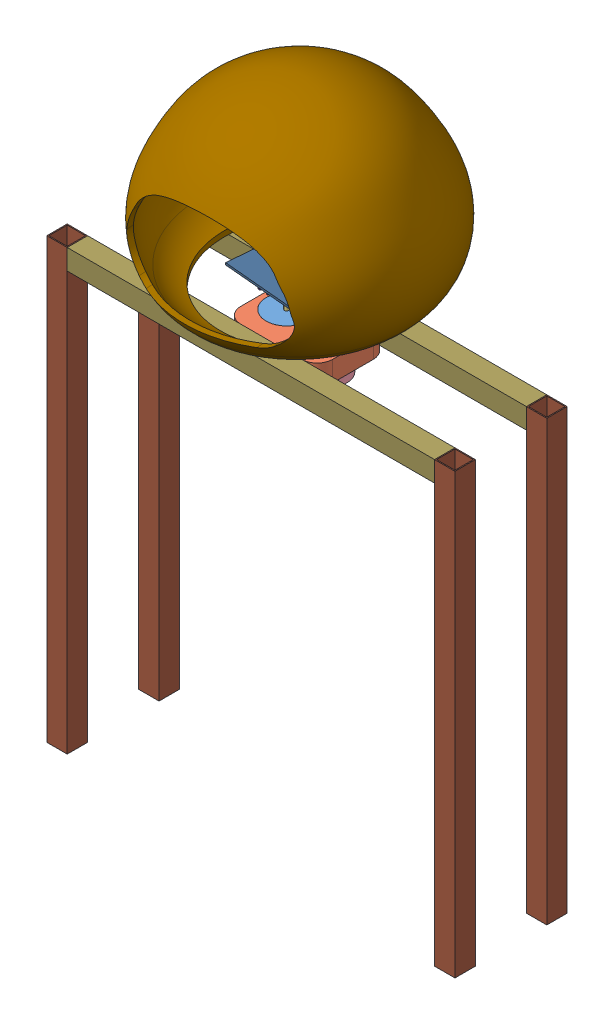
SolidWorks assembly Assemminubotmechanism1, configuration Default. Lengths in mm.
Overall size (400 641.82 258.29).
25 component instances, 13 part files, 41 mates.
Components (placement in the parent):
- motor-1: motor [Default] at (41.8736 82.6151 282.3269) x (-0.996078 0 -0.088478) z (0.08601 0.234536 -0.968295) size (40 40 40)
- motor-2: motor [Default] at (-7.9303 10.615 277.903) x (0 -1 0) z (0.040823 0 0.999166) size (40 40 40)
- support-2: support [Default] at (107.0697 -79.385 138.7286) x (-1 0 0) z (0 0 -1) size (50 90 70) (hidden)
- motorholder-2: motorholder [Default] at (12.0697 -9.385 277.903) x (1 0 0) z (0 1 0) size (90 70 20)
- motorshaft-1: motorshaft [Default] at (-7.9303 30.615 277.903) x (0.099455 0 -0.995042) z (0 -1 0) size (4 4 20)
- encoder-1: encoder [Default] at (32.0697 -22.385 277.903) x (0 1 0) z (-0.896169 0 0.443712) size (33 38 38)
- encoder-2: encoder [Default] at (9.003 122.6151 279.4071) x (0.996078 0 0.088478) z (0.000918 -0.999946 -0.01033) size (33 38 38)
- motorshaft-2: motorshaft [Default] at (61.7951 82.6151 284.0965) x (-0.033785 0.924225 0.380352) z (-0.996078 0 -0.088478) size (4 4 20)
- encodershaft-2: encodershaft [Default] at (41.8736 122.6151 282.3269) x (-0.064638 0.682856 0.727688) z (0.996078 0 0.088478) size (3 3 15)
- encodershaft-3: encodershaft [Default] at (32.0697 25.615 277.903) x (0.479617 0 -0.877478) z (0 -1 0) size (3 3 15)
- l link1-1: l link1 [Default] at (81.4955 53.9444 254.4504) x (-0.003837 0.999059 0.043201) z (-0.088395 -0.043371 0.995141) size (112 115 60)
- encodershaftcoupling-1: encodershaftcoupling [Default] at (32.0697 40.615 277.903) x (-0.852707 0 -0.522389) z (0 -1 0) size (10 10 15)
- encodershaftcoupling-2: encodershaftcoupling [Default] at (71.7559 122.6151 284.9813) x (0.065115 0.677039 -0.733061) z (-0.996078 0 -0.088478) size (10 10 15)
- spur gear_am-12: spur gear_am [Metric - Spur gear 2.5M 16T 20PA 10FW ---S16O15H20L10N] at (-7.9303 35.6151 277.903) x (0 1 0) z (-0.944824 0 0.327578) size (20 44.35 44.35)
- spur gear_am-13: spur gear_am [Metric - Spur gear 2.5M 16T 20PA 10FW ---S16O15H20L10N] at (32.0697 35.6151 277.903) x (0 1 0) z (0.661693 0 -0.749775) size (20 44.35 44.35)
- spur gear_am-14: spur gear_am [Metric - Spur gear 2.5M 16T 20PA 10FW ---S16O15H20L10N] at (66.7756 122.6151 284.5389) x (0.996078 0 0.088478) z (-0.048006 -0.840007 0.540447) size (20 44.35 44.35)
- spur gear_am-15: spur gear_am [Metric - Spur gear 2.5M 16T 20PA 10FW ---S16O15H20L10N] at (66.7756 82.6151 284.5389) x (0.996078 0 0.088478) z (-0.043333 -0.871856 0.487842) size (20 44.35 44.35)
- FaceEVE2-1: FaceEVE2 [Default] at (7.0992 59.6367 278.2366) x (0.035057 -0.04304 0.998458) z (-0.999378 -0.005346 0.034859) size (242.26 184.23 242.26)
- l link-2: l link [Default] at (14.489 70.3565 310.0125) x (-0.996078 0 -0.088478) z (0.088478 0 -0.996078) size (80 100 60)
- head channel430mm-1: head channel430mm [Default] at (-187.9303 -419.385 222.903) x (1 0 0) z (0 1 0) size (20 20 430)
- head channel430mm-2: head channel430mm [Default] at (-187.9303 10.615 332.903) x (1 0 0) z (0 -1 0) size (20 20 430)
- head channel-5: head channel [Default] at (192.0697 10.615 222.903) x (0 0 1) z (-1 0 0) size (20 20 360)
- head channel-6: head channel [Default] at (-167.9303 10.615 332.903) x (0 0 -1) z (1 0 0) size (20 20 360)
- head channel430mm-5: head channel430mm [Default] at (212.0697 -419.385 332.903) x (-1 0 0) z (0 1 0) size (20 20 430)
- head channel430mm-6: head channel430mm [Default] at (212.0697 10.615 222.903) x (-1 0 0) z (0 -1 0) size (20 20 430)
Mates (geometry in assembly coordinates):
- Coincident1: coincident anti-aligned: circle of motor-2; circle of motorshaft-1
- Coincident2: coincident anti-aligned: circle of motor-1; circle of motorshaft-2
- Coincident6: coincident aligned: circle of encoder-2; circle of encodershaft-2
- Coincident11: coincident anti-aligned: cylinder of motor-2 through (-7.9303 -29.385 277.903) axis (0 1 0) radius 20; circle of motorholder-2
- Coincident17: coincident anti-aligned: line of support-2 through (57.0697 10.615 68.7286) axis (0 0 1); line of motorholder-2 through (57.0697 10.615 297.903) axis (0 0 -1)
- Coincident18: coincident anti-aligned: plane of support-2 through (57.0697 -79.385 68.7286) normal (-1 0 0); plane of motorholder-2 through (57.0697 10.615 297.903) normal (1 0 0)
- Coincident28: coincident aligned: plane of motor-2 through (-7.9303 10.615 277.903) normal (0 1 0); plane of motorholder-2 through (-17.9303 10.615 297.903) normal (0 1 0)
- Concentric9: concentric aligned: circle of encodershaft-3; circle of encodershaftcoupling-1
- Concentric12: concentric anti-aligned: circle of encodershaft-2; circle of encodershaftcoupling-2
- Coincident76: coincident aligned: circle of motorholder-2; circle of encoder-1
- Coincident77: coincident anti-aligned: circle of encoder-1; circle of encodershaft-3
- Coincident92: coincident anti-aligned: circle of encodershaftcoupling-1; circle of spur gear_am-13
- GearMate2: gear = 15 : 15 mm: circle of spur gear_am-12; circle of spur gear_am-13
- Coincident95: coincident anti-aligned: circle of encodershaftcoupling-2; circle of spur gear_am-14
- GearMate3: gear = 15 : 15 mm: circle of spur gear_am-14; circle of spur gear_am-15
- Coincident97: coincident aligned: circle of motor-1; circle of l link-2
- Coincident98: coincident anti-aligned: circle of encoder-2; circle of l link-2
- Width1: width anti-aligned: plane of head channel-6 through (192.0697 10.615 332.903) normal (1 0 0); plane of head channel-6 through (-167.9303 10.615 332.903) normal (-1 0 0); plane of motorholder-2 through (-32.9303 10.615 297.903) normal (-1 0 0); plane of motorholder-2 through (57.0697 10.615 297.903) normal (1 0 0)
- Coincident102: coincident anti-aligned: line of motorholder-2 through (-17.9303 10.615 312.903) axis (1 0 0); line of head channel-6 through (192.0697 10.615 312.903) axis (-1 0 0)
- Coincident103: coincident anti-aligned: plane of motorholder-2 through (42.0697 10.615 312.903) normal (0 0 1); plane of head channel-6 through (192.0697 10.615 312.903) normal (0 0 -1)
- Coincident104: coincident anti-aligned: plane of motorholder-2 through (42.0697 10.615 242.903) normal (0 0 -1); plane of head channel-5 through (-167.9303 10.615 242.903) normal (0 0 1)
- Width2: width aligned: plane of head channel-5 through (-167.9303 10.615 222.903) normal (-1 0 0); plane of head channel-5 through (192.0697 10.615 222.903) normal (1 0 0); plane of motorholder-2 through (-32.9303 10.615 297.903) normal (-1 0 0); plane of motorholder-2 through (57.0697 10.615 297.903) normal (1 0 0)
- Coincident105: coincident anti-aligned: line of motorholder-2 through (42.0697 10.615 242.903) axis (-1 0 0); line of head channel-5 through (-167.9303 10.615 242.903) axis (1 0 0)
- Coincident106: coincident aligned: line of head channel430mm-2 through (-167.9303 10.615 312.903) axis (0 0 1); line of head channel-6 through (-167.9303 10.615 312.903) axis (0 0 1)
- Coincident110: coincident aligned: plane of head channel430mm-2 through (-187.9303 -419.385 332.903) normal (0 0 1); plane of head channel-6 through (192.0697 10.615 332.903) normal (0 0 1)
- Coincident109: coincident aligned: plane of head channel430mm-2 through (-187.9303 10.615 332.903) normal (0 1 0); plane of head channel-6 through (192.0697 10.615 332.903) normal (0 1 0)
- Coincident111: coincident aligned: line of head channel430mm-1 through (-167.9303 10.615 242.903) axis (0 0 -1); line of head channel-5 through (-167.9303 10.615 242.903) axis (0 0 -1)
- Coincident112: coincident aligned: plane of head channel430mm-1 through (-187.9303 10.615 222.903) normal (0 1 0); plane of head channel-5 through (-167.9303 10.615 222.903) normal (0 1 0)
- Coincident113: coincident aligned: plane of head channel430mm-1 through (-187.9303 10.615 242.903) normal (0 0 1); plane of head channel-5 through (-167.9303 10.615 242.903) normal (0 0 1)
- Concentric26: concentric anti-aligned: circle of l link1-1; circle of FaceEVE2-1
- Coincident114: coincident anti-aligned: plane of l link1-1 through (65.8012 163.2368 318.1125) normal (-0.003837 0.999059 0.043201); plane of FaceEVE2-1 through (6.6962 164.5379 282.7726) normal (0.003837 -0.999059 -0.043201)
- Concentric27: concentric aligned: cylinder of motorshaft-1 through (-7.9303 10.615 277.903) axis (0 1 0) radius 2; circle of spur gear_am-12
- Concentric28: concentric aligned: cylinder of motorshaft-2 through (41.8736 82.6151 282.3269) axis (0.996078 0 0.088478) radius 2; circle of spur gear_am-15
- Concentric29: concentric aligned: circle of spur gear_am-12; circle of l link-2
- Coincident117: coincident anti-aligned: plane of spur gear_am-12 through (-7.9303 45.6151 277.903) normal (0 1 0); plane of l link-2 through (-35.1583 45.6151 245.3663) normal (0 -1 0)
- Concentric30: concentric anti-aligned: circle of l link1-1; circle of spur gear_am-15
- Coincident118: coincident anti-aligned: plane of l link1-1 through (74.1996 51.3422 313.9819) normal (-0.996078 0 -0.088478); plane of spur gear_am-15 through (76.7364 82.6151 285.4236) normal (0.996078 0 0.088478)
- Distance1: distance = 15 mm anti-aligned: plane of spur gear_am-12 through (-7.9303 25.615 277.903) normal (0 -1 0); plane of motor-2 through (-7.9303 10.615 277.903) normal (0 1 0)
- Distance3: distance = 15 mm anti-aligned: plane of spur gear_am-15 through (56.8147 82.6151 283.6541) normal (-0.996078 0 -0.088478); plane of motor-1 through (41.8736 82.6151 282.3269) normal (0.996078 0 0.088478)
- Coincident121: coincident aligned: plane of spur gear_am-14 through (56.8147 122.6151 283.6541) normal (-0.996078 0 -0.088478); plane of spur gear_am-15 through (56.8147 82.6151 283.6541) normal (-0.996078 0 -0.088478)
- Coincident122: coincident aligned: plane of spur gear_am-12 through (-7.9303 25.615 277.903) normal (0 -1 0); plane of spur gear_am-13 through (32.0697 25.615 277.903) normal (0 -1 0)
